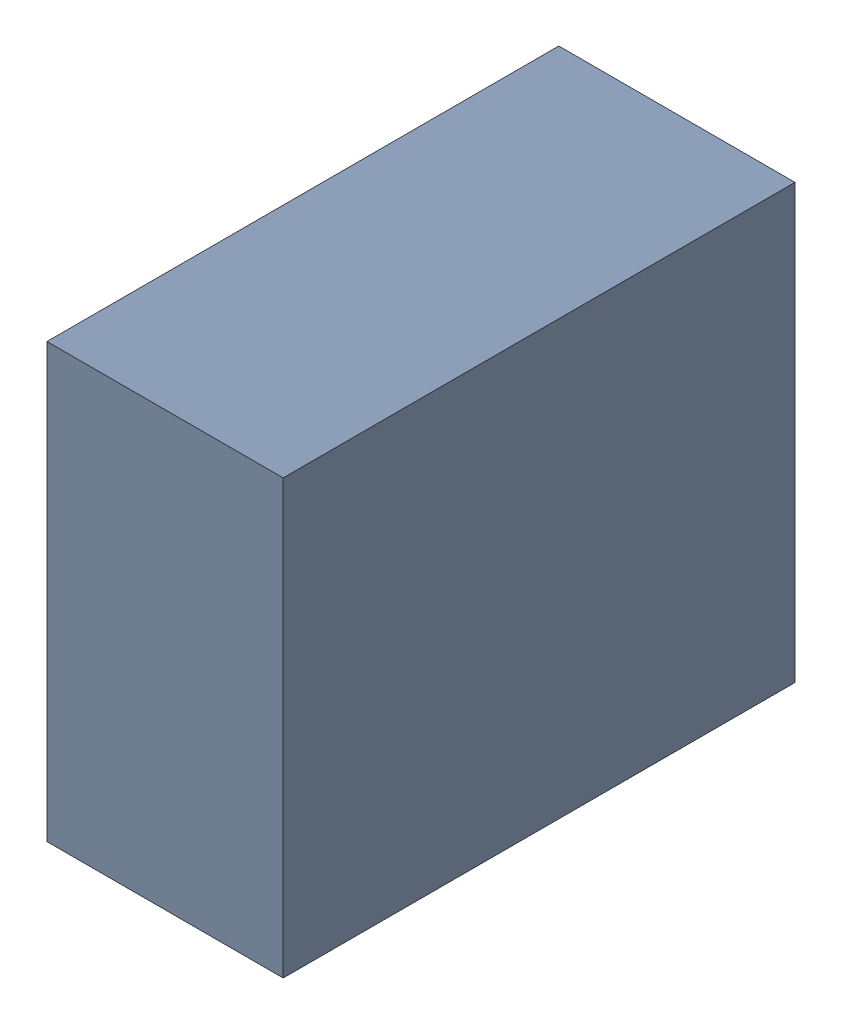
SolidWorks assembly C23_TDA4, configuration Standard. Lengths in mm.
Overall size (0.6 1.1 1.3).
2 component instances, 1 part files, 0 mates.
Components (placement in the parent):
- 885542376-1: 885542376 [Standard] at (-4.31 -51.19 0) size (0.6 1.1 1.3)
  - Extruded_25-1: Extruded_25 [Standard] at origin size (0.6 1.1 1.3)
